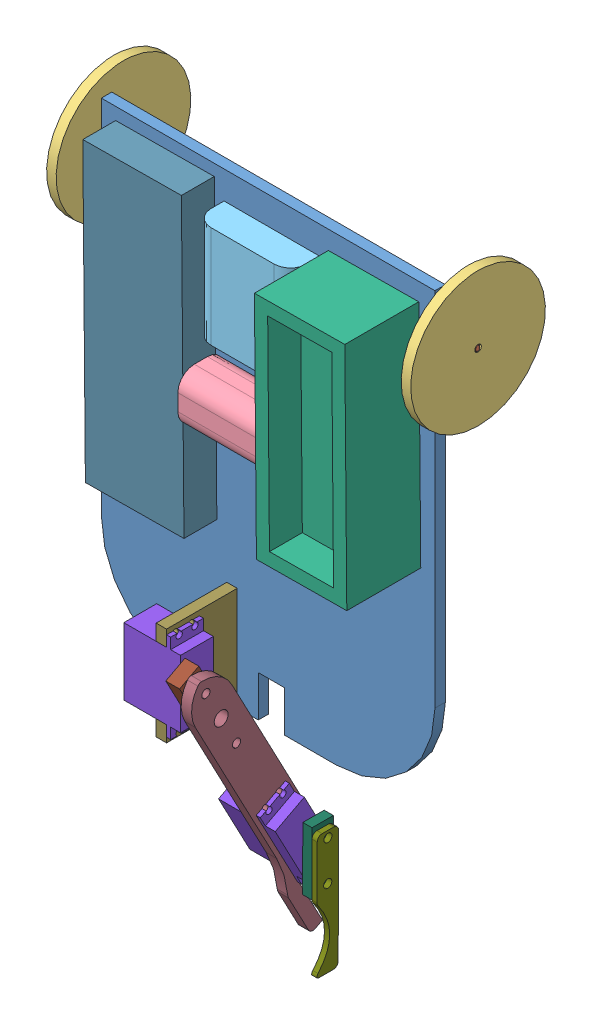
SolidWorks assembly ASM_Brobot, configuration Default. Lengths in mm.
Overall size (221.56 416.16 121.18).
25 component instances, 16 part files, 43 mates.
Components (placement in the parent):
- BrobotBase-1: BrobotBase [Default] at (-30.6014 -29.7494 33.1843) size (203 280 6.35)
- ASM_WheelMotor-1: ASM_WheelMotor [Default] at (-92.0356 84.9156 15.7307) x (1 0 0) z (0 -1 0) size (57.8 82 82)
  - PololuMotor_73to1-1: PololuMotor_73to1 [Default] at (-36.3458 6.8547 6.132) size (57.8 20.5 20.5)
  - Wheel-1: Wheel [Default] at (-49.3458 6.8547 6.132) x (0 0 -1) z (1 0 0) size (82 82 5.8)
- ASM_WheelMotor-2: ASM_WheelMotor [Default] at (30.8328 82.2016 29.4402) x (-1 0 0) z (0 -1 0) size (57.8 82 82)
  - PololuMotor_73to1-1: PololuMotor_73to1 [Default] at (-36.3458 6.8547 6.132) size (57.8 20.5 20.5)
  - Wheel-1: Wheel [Default] at (-49.3458 6.8547 6.132) x (0 0 -1) z (1 0 0) size (82 82 5.8)
- BatteryPackRectangle-1: BatteryPackRectangle [Default] at (-29.0634 1.2624 39.5343) x (0 1 0) z (0 0 1) size (30 57 28)
- BatteryPackSquare-1: BatteryPackSquare [Default] at (-28.1781 62.3403 39.5343) size (58.5 62 18)
- BreadBoard-1: BreadBoard [Default] at (34.1543 29.3954 39.5343) x (-0.999962 -0.008727 0) z (0 0 1) size (55 139.7 45)
- CasterWheel-1: CasterWheel [Default] at (-22.6443 -129.4461 7.7843) x (-0.923728 -0.383049 0) z (0 0 -1) size (22.32 22.38 27.76)
- PowerHD_1501MG_Servo-1: PowerHD_1501MG_Servo [Default] at (-49.4264 -136.7494 72.5343) x (0 -1 0) z (1 0 0) size (54 20 38)
- PowerHD_1501MG_Servo-2: PowerHD_1501MG_Servo [Default] at (-26.1764 -228.1597 29.7804) x (0 -0.884392 -0.466745) z (1 0 0) size (54 20 38)
- CasterWheelExtension-1: CasterWheelExtension [Default] at (-22.6443 -129.4461 20.4843) size (22 22 6.35)
- CasterWheelExtension-2: CasterWheelExtension [Default] at (-22.6443 -129.4461 33.1843) x (-0.923728 -0.383049 0) z (0 0 -1) size (22 22 6.35)
- CasterWheelExtension-3: CasterWheelExtension [Default] at (-22.6443 -129.4461 14.1343) size (22 22 6.35)
- CasterWheelExtension-4: CasterWheelExtension [Default] at (-22.6443 -129.4461 7.7843) size (22 22 6.35)
- MotorHoldPlateBottom-1: MotorHoldPlateBottom [Default] at (-111.1814 50.2506 30.0855) x (-1 0 0) z (0 1 0) size (25.4 3.1 38.1)
- MotorHoldPlateBottom-2: MotorHoldPlateBottom [Default] at (24.5786 50.2506 30.0855) x (-1 0 0) z (0 1 0) size (25.4 3.1 38.1)
- ServoHorn1-1: ServoHorn1 [Default] at (-32.5264 -147.1494 72.5343) x (0 0.884392 0.466745) z (-1 0 0) size (56.25 13.25 8.4)
- ServoHolder-1: ServoHolder [Default] at (-49.4264 -136.7494 61.0343) x (0 -1 0) z (-1 0 0) size (60 49.35 6.35)
- Arm-1: Arm [Default] at (-32.5264 -186.947 51.5307) x (0 0.884392 0.466745) z (1 0 0) size (178.26 30 6.35)
- BeagleBone-1: BeagleBone [Default] at (-92.5978 13.0387 39.5343) x (-0.008727 0.999962 0) z (0 0 1) size (180 60 20)
- ServoHorn2-1: ServoHorn2 [Default] at (-12.0764 -237.3574 24.9262) x (0 0.999994 -0.00351) z (-1 0 0) size (38 13 5.6)
- Gripper-1: Gripper [Default] at (-12.0764 -258.8572 25.0017) x (0 0.999994 -0.00351) z (1 0 0) size (75 13 3.17)
Mates (geometry in assembly coordinates):
- Coincident1: coincident anti-aligned: plane of BrobotBase-1 through (70.8986 110.2506 39.5343) normal (0 0 1); plane of BreadBoard-1 through (62.2628 -40.2119 39.5343) normal (0 0 -1)
- Coincident3: coincident anti-aligned: plane of BrobotBase-1 through (70.8986 110.2506 33.1843) normal (0 0 -1); plane of MotorHoldPlateBottom-1 through (-85.7814 69.3006 33.1843) normal (0 0 1)
- Concentric5: concentric anti-aligned: cylinder of BrobotBase-1 through (-90.8614 34.3756 29.0123) axis (0 0 1) radius 1.475; cylinder of MotorHoldPlateBottom-1 through (-90.8614 34.3756 33.1843) axis (0 0 -1) radius 1.4732
- Concentric6: concentric anti-aligned: cylinder of BrobotBase-1 through (-106.1014 66.1256 29.0123) axis (0 0 1) radius 1.475; cylinder of MotorHoldPlateBottom-1 through (-106.1014 66.1256 33.1843) axis (0 0 -1) radius 1.4732
- Coincident4: coincident anti-aligned: plane of ASM_WheelMotor-1/PololuMotor_73to1-1 through (-86.0814 71.8706 30.0855) normal (0 0 1); plane of MotorHoldPlateBottom-1 through (-85.7814 69.3006 30.0855) normal (0 0 -1)
- Coincident5: coincident anti-aligned: plane of ASM_WheelMotor-1/PololuMotor_73to1-1 through (-111.1814 78.7836 22.5855) normal (1 0 0); plane of MotorHoldPlateBottom-1 through (-111.1814 31.2006 33.1843) normal (-1 0 0)
- Concentric8: concentric anti-aligned: cylinder of BrobotBase-1 through (29.6586 66.1256 29.0123) axis (0 0 1) radius 1.475; cylinder of MotorHoldPlateBottom-2 through (29.6586 66.1256 33.1843) axis (0 0 -1) radius 1.4732
- Concentric9: concentric anti-aligned: cylinder of BrobotBase-1 through (44.8986 34.3756 29.0123) axis (0 0 1) radius 1.475; cylinder of MotorHoldPlateBottom-2 through (44.8986 34.3756 33.1843) axis (0 0 -1) radius 1.4732
- Coincident6: coincident anti-aligned: plane of BrobotBase-1 through (70.8986 110.2506 33.1843) normal (0 0 -1); plane of MotorHoldPlateBottom-2 through (49.9786 69.3006 33.1843) normal (0 0 1)
- Coincident8: coincident anti-aligned: plane of ASM_WheelMotor-2/PololuMotor_73to1-1 through (49.9786 76.0696 22.5855) normal (-1 0 0); plane of MotorHoldPlateBottom-2 through (49.9786 31.2006 33.1843) normal (1 0 0)
- Coincident9: coincident anti-aligned: plane of ASM_WheelMotor-2/PololuMotor_73to1-1 through (24.8786 69.1566 30.0855) normal (0 0 1); plane of MotorHoldPlateBottom-2 through (49.9786 69.3006 30.0855) normal (0 0 -1)
- Coincident10: coincident anti-aligned: plane of BrobotBase-1 through (70.8986 110.2506 39.5343) normal (0 0 1); plane of BatteryPackSquare-1 through (1.0719 93.3403 39.5343) normal (0 0 -1)
- Coincident11: coincident anti-aligned: plane of CasterWheelExtension-1 through (-22.6443 -129.4461 26.8343) normal (0 0 1); plane of CasterWheelExtension-2 through (-22.6443 -129.4461 26.8343) normal (0 0 -1)
- Concentric10: concentric anti-aligned: cylinder of CasterWheelExtension-1 through (-22.6443 -129.4461 26.8343) axis (0 0 -1) radius 11; cylinder of CasterWheelExtension-2 through (-22.6443 -129.4461 26.8343) axis (0 0 1) radius 11
- Concentric11: concentric aligned: cylinder of CasterWheelExtension-1 through (-22.6443 -129.4461 26.8343) axis (0 0 -1) radius 11; cylinder of CasterWheelExtension-3 through (-22.6443 -129.4461 20.4843) axis (0 0 -1) radius 11
- Coincident12: coincident anti-aligned: plane of CasterWheelExtension-1 through (-22.6443 -129.4461 20.4843) normal (0 0 -1); plane of CasterWheelExtension-3 through (-22.6443 -129.4461 20.4843) normal (0 0 1)
- Coincident13: coincident anti-aligned: plane of CasterWheelExtension-3 through (-22.6443 -129.4461 14.1343) normal (0 0 -1); plane of CasterWheelExtension-4 through (-22.6443 -129.4461 14.1343) normal (0 0 1)
- Concentric12: concentric aligned: cylinder of CasterWheelExtension-3 through (-22.6443 -129.4461 20.4843) axis (0 0 -1) radius 11; cylinder of CasterWheelExtension-4 through (-22.6443 -129.4461 14.1343) axis (0 0 -1) radius 11
- Coincident14: coincident anti-aligned: plane of CasterWheel-1 through (-22.6443 -129.4461 7.7843) normal (0 0 1); plane of CasterWheelExtension-4 through (-22.6443 -129.4461 7.7843) normal (0 0 -1)
- Concentric13: concentric anti-aligned: cylinder of CasterWheel-1 through (-22.6443 -129.4461 -8.2157) axis (0 0 1) radius 11; cylinder of CasterWheelExtension-4 through (-22.6443 -129.4461 14.1343) axis (0 0 -1) radius 11
- Coincident16: coincident anti-aligned: plane of BrobotBase-1 through (70.8986 110.2506 39.5343) normal (0 0 1); plane of BatteryPackRectangle-1 through (-57.5634 16.2624 39.5343) normal (0 0 -1)
- Coincident17: coincident anti-aligned: plane of BrobotBase-1 through (70.8986 110.2506 33.1843) normal (0 0 -1); plane of CasterWheelExtension-2 through (-22.6443 -129.4461 33.1843) normal (0 0 1)
- Concentric14: concentric anti-aligned: cylinder of PowerHD_1501MG_Servo-1 through (-37.4264 -147.1494 72.5343) axis (-1 0 0) radius 2.9; cylinder of ServoHorn1-1 through (-40.9264 -147.1494 72.5343) axis (1 0 0) radius 2.9
- Coincident19: coincident anti-aligned: plane of PowerHD_1501MG_Servo-1 through (-40.9264 -157.1494 62.5343) normal (1 0 0); plane of ServoHorn1-1 through (-40.9264 -119.1837 79.8024) normal (-1 0 0)
- Parallel1: parallel anti-aligned: plane of BrobotBase-1 through (70.8986 110.2506 39.5343) normal (0 0 1); plane of PowerHD_1501MG_Servo-1 through (-46.9264 -109.7494 62.5343) normal (0 0 -1)
- Coincident21: coincident anti-aligned: plane of PowerHD_1501MG_Servo-1 through (-49.4264 -163.7494 62.5343) normal (-1 0 0); plane of ServoHolder-1 through (-49.4264 -166.7494 82.5343) normal (1 0 0)
- Concentric16: concentric anti-aligned: cylinder of PowerHD_1501MG_Servo-1 through (-54.9418 -162.2494 77.3343) axis (1 0 0) radius 1.95; cylinder of ServoHolder-1 through (-3.9881 -162.2494 77.3343) axis (-1 0 0) radius 1.95
- Concentric17: concentric anti-aligned: cylinder of PowerHD_1501MG_Servo-1 through (-54.9418 -162.2494 67.7343) axis (1 0 0) radius 1.95; cylinder of ServoHolder-1 through (-3.9881 -162.2494 67.7343) axis (-1 0 0) radius 1.95
- Coincident23: coincident anti-aligned: plane of BrobotBase-1 through (-55.7764 -106.7494 3.5026) normal (1 0 0); plane of ServoHolder-1 through (-55.7764 -166.7494 82.5343) normal (-1 0 0)
- Coincident25: coincident anti-aligned: plane of BrobotBase-1 through (-49.4264 -166.7494 3.5026) normal (0 1 0); plane of ServoHolder-1 through (-55.7764 -166.7494 39.5343) normal (0 -1 0)
- Coincident26: coincident anti-aligned: plane of BrobotBase-1 through (70.8986 110.2506 39.5343) normal (0 0 1); plane of ServoHolder-1 through (-55.7764 -154.7494 39.5343) normal (0 0 -1)
- Coincident27: coincident anti-aligned: plane of ServoHorn1-1 through (-32.5264 -119.1837 79.8024) normal (1 0 0); plane of Arm-1 through (-32.5264 -247.4421 5.4699) normal (-1 0 0)
- Concentric18: concentric anti-aligned: cylinder of ServoHorn1-1 through (-40.9264 -129.4616 81.8692) axis (1 0 0) radius 2.5; cylinder of Arm-1 through (-26.1764 -129.4616 81.8692) axis (-1 0 0) radius 2.5
- Concentric20: concentric anti-aligned: cylinder of ServoHorn1-1 through (-40.9264 -164.8373 63.1993) axis (1 0 0) radius 2.5; cylinder of Arm-1 through (-26.1764 -164.8373 63.1993) axis (-1 0 0) radius 2.5
- Coincident28: coincident anti-aligned: plane of PowerHD_1501MG_Servo-2 through (-26.1764 -247.3708 8.3343) normal (-1 0 0); plane of Arm-1 through (-26.1764 -247.4421 5.4699) normal (1 0 0)
- Concentric21: concentric aligned: cylinder of PowerHD_1501MG_Servo-2 through (-31.6918 -252.9521 22.1235) axis (1 0 0) radius 1.95; cylinder of Arm-1 through (-77.9647 -252.9521 22.1235) axis (1 0 0) radius 1.95
- Concentric22: concentric aligned: cylinder of PowerHD_1501MG_Servo-2 through (-31.6918 -203.3673 37.4373) axis (1 0 0) radius 1.95; cylinder of Arm-1 through (-77.9647 -203.3673 37.4373) axis (1 0 0) radius 1.95
- Coincident29: coincident anti-aligned: plane of BrobotBase-1 through (70.8986 110.2506 39.5343) normal (0 0 1); plane of BeagleBone-1 through (-123.3821 102.7735 39.5343) normal (0 0 -1)
- Concentric23: concentric anti-aligned: cylinder of PowerHD_1501MG_Servo-2 through (-14.1764 -237.3574 24.9262) axis (-1 0 0) radius 2.9; cylinder of ServoHorn2-1 through (-17.6764 -237.3574 24.9262) axis (1 0 0) radius 2.9
- Coincident30: coincident anti-aligned: plane of PowerHD_1501MG_Servo-2 through (-17.6764 -241.5338 11.4149) normal (1 0 0); plane of ServoHorn2-1 through (-17.6764 -218.3803 18.3596) normal (-1 0 0)
- Concentric24: concentric anti-aligned: cylinder of ServoHorn2-1 through (-17.6764 -225.3574 24.8841) axis (1 0 0) radius 2.5; cylinder of Gripper-1 through (-8.9014 -225.3574 24.8841) axis (-1 0 0) radius 2.5
- Concentric25: concentric anti-aligned: cylinder of ServoHorn2-1 through (-17.6764 -249.3573 24.9683) axis (1 0 0) radius 2.5; cylinder of Gripper-1 through (-8.9014 -249.3573 24.9683) axis (-1 0 0) radius 2.5
- Coincident31: coincident anti-aligned: plane of ServoHorn2-1 through (-12.0764 -218.3803 18.3596) normal (1 0 0); plane of Gripper-1 through (-12.0764 -221.3347 31.37) normal (-1 0 0)
